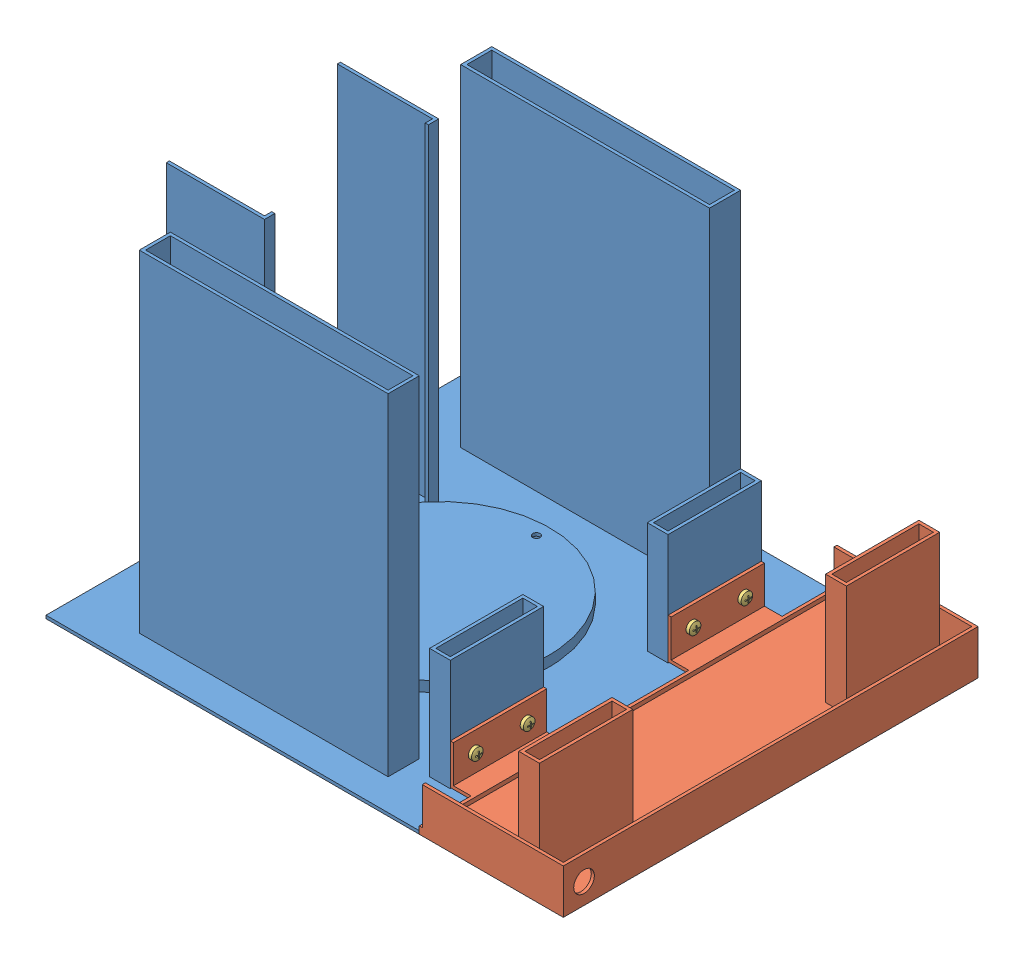
SolidWorks assembly Base, configuration Valor predeterminado. Lengths in mm.
Overall size (249.5 161.5 200).
10 component instances, 4 part files, 19 mates.
Components (placement in the parent):
- 27AA - Base-1: 27AA - Base [Valor predeterminado] at (-634.4278 -116.9568 382.968) x (1 0 0) z (0 -1 0) size (180 200 161.5)
- 18R -Base traseira-1: 18R -Base traseira [Valor predeterminado] at (-634.9278 -116.9568 382.968) x (1 0 0) z (0 -1 0) size (79.5 200 55.15)
- M3x16-1: M3x16 [Default] at (-552.9278 -205.9568 317.968) x (-1 0 0) z (0 -1 0) size (18.37 5.6 5.6)
- M3x16-2: M3x16 [Default] at (-552.9278 -205.9568 342.968) x (-1 0 0) z (0 0 -1) size (18.37 5.6 5.6)
- M3x16-3: M3x16 [Default] at (-552.9278 -205.9568 422.968) x (-1 0 0) z (0 0 -1) size (18.37 5.6 5.6)
- M3x16-4: M3x16 [Default] at (-552.9278 -205.9568 447.968) x (-1 0 0) z (0 0 -1) size (18.37 5.6 5.6)
- Porca M3-1: Porca M3 [Default] at (-566.8278 -205.9568 447.968) size (2.41 6.36 6.36)
- Porca M3-2: Porca M3 [Default] at (-566.8278 -205.9568 342.968) size (2.41 6.36 6.36)
- Porca M3-3: Porca M3 [Default] at (-566.8278 -205.9568 317.968) size (2.41 6.36 6.36)
- Porca M3-4: Porca M3 [Default] at (-566.8278 -205.9568 422.968) size (2.41 6.36 6.36)
Mates (geometry in assembly coordinates):
- Coincidente1: coincident aligned: plane of 27AA - Base-1 through (-634.4278 -218.4568 382.968) normal (0 -1 0); plane of 18R -Base traseira-1 through (-634.9278 -218.4568 382.968) normal (0 -1 0)
- Coincidente2: coincident aligned: plane of 27AA - Base-1 through (-724.4278 -216.9568 282.968) normal (0 0 -1); plane of 18R -Base traseira-1 through (-544.4278 -218.4568 282.968) normal (0 0 -1)
- Coincidente3: coincident aligned: circle of 27AA - Base-1; circle of 18R -Base traseira-1
- Concêntrico1: concentric aligned: cylinder of 18R -Base traseira-1 through (-570.019 -205.9568 317.968) axis (1 0 0) radius 1.8; cylinder of M3x16-1 through (-561.4278 -205.9568 317.968) axis (1 0 0) radius 1.5
- Coincidente4: coincident: plane of 18R -Base traseira-1 through (-552.9278 -151.9318 307.968) normal (1 0 0); plane of M3x16-1 through (-552.9278 -205.9568 315.668) normal (-1 0 0)
- Concêntrico2: concentric aligned: cylinder of 18R -Base traseira-1 through (-570.019 -205.9568 342.968) axis (1 0 0) radius 1.8; cylinder of M3x16-2 through (-561.4278 -205.9568 342.968) axis (1 0 0) radius 1.5
- Coincidente5: coincident anti-aligned: plane of 18R -Base traseira-1 through (-552.9278 -151.9318 307.968) normal (1 0 0); plane of M3x16-2 through (-552.9278 -203.6568 342.968) normal (-1 0 0)
- Concêntrico3: concentric aligned: cylinder of 18R -Base traseira-1 through (-570.019 -205.9568 422.968) axis (1 0 0) radius 1.8; cylinder of M3x16-3 through (-561.4278 -205.9568 422.968) axis (1 0 0) radius 1.5
- Coincidente6: coincident: plane of 18R -Base traseira-1 through (-552.9278 -151.9318 412.968) normal (1 0 0); plane of M3x16-3 through (-552.9278 -203.6568 422.968) normal (-1 0 0)
- Concêntrico4: concentric aligned: cylinder of 18R -Base traseira-1 through (-570.019 -205.9568 447.968) axis (1 0 0) radius 1.8; cylinder of M3x16-4 through (-561.4278 -205.9568 447.968) axis (1 0 0) radius 1.5
- Coincidente7: coincident anti-aligned: plane of 18R -Base traseira-1 through (-552.9278 -151.9318 412.968) normal (1 0 0); plane of M3x16-4 through (-552.9278 -203.6568 447.968) normal (-1 0 0)
- Coincidente8: coincident anti-aligned: plane of 27AA - Base-1 through (-564.4278 -196.9568 307.968) normal (-1 0 0); plane of Porca M3-3 through (-564.4278 -203.2068 317.968) normal (1 0 0)
- Coincidente9: coincident anti-aligned: plane of 27AA - Base-1 through (-564.4278 -196.9568 307.968) normal (-1 0 0); plane of Porca M3-2 through (-564.4278 -203.2068 342.968) normal (1 0 0)
- Coincidente10: coincident anti-aligned: plane of 27AA - Base-1 through (-564.4278 -196.9568 457.968) normal (-1 0 0); plane of Porca M3-4 through (-564.4278 -203.2068 422.968) normal (1 0 0)
- Coincidente11: coincident: plane of 27AA - Base-1 through (-564.4278 -196.9568 457.968) normal (-1 0 0); plane of Porca M3-1 through (-564.4278 -203.2068 447.968) normal (1 0 0)
- Concêntrico6: concentric anti-aligned: cylinder of M3x16-4 through (-561.4278 -205.9568 447.968) axis (1 0 0) radius 1.5; cylinder of Porca M3-1 through (-564.4278 -205.9568 447.968) axis (-1 0 0) radius 1.2295
- Concêntrico7: concentric anti-aligned: cylinder of M3x16-3 through (-561.4278 -205.9568 422.968) axis (1 0 0) radius 1.5; cylinder of Porca M3-4 through (-564.4278 -205.9568 422.968) axis (-1 0 0) radius 1.2295
- Concêntrico8: concentric aligned: cylinder of M3x16-1 through (-561.4278 -205.9568 317.968) axis (1 0 0) radius 1.5; cone of Porca M3-3 through (-566.8278 -205.9568 317.968) axis (1 0 0)
- Concêntrico9: concentric aligned: cylinder of M3x16-2 through (-561.4278 -205.9568 342.968) axis (1 0 0) radius 1.5; cone of Porca M3-2 through (-566.8278 -205.9568 342.968) axis (1 0 0)
